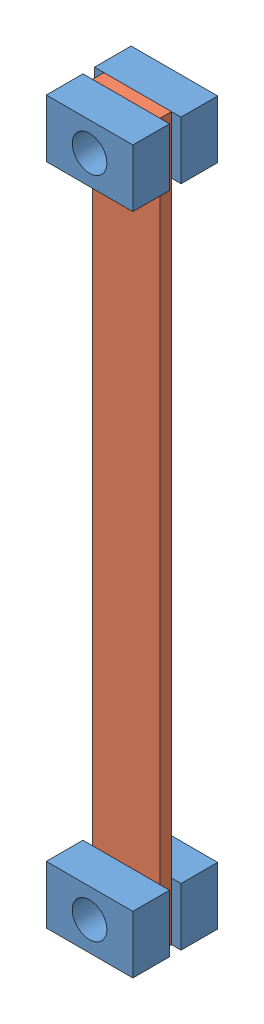
SolidWorks assembly Flywheel_CN_V2, configuration Default. Lengths in mm.
Overall size (15 125 14.7).
5 component instances, 2 part files, 11 mates.
Components (placement in the parent):
- PlaqueEpaisseFlywheel_CN_V2-1: PlaqueEpaisseFlywheel_CN_V2 [Default] at (0 57.5 1) size (15 10 6.35)
- PlaqueMinceFlywheel_CN_V2-1: PlaqueMinceFlywheel_CN_V2 [Default] x (-1 0 0) z (0 0 -1) size (11.7 125 2)
- PlaqueEpaisseFlywheel_CN_V2-2: PlaqueEpaisseFlywheel_CN_V2 [Default] at (0 -57.5 -1) x (-1 0 0) z (0 0 -1) size (15 10 6.35)
- PlaqueEpaisseFlywheel_CN_V2-3: PlaqueEpaisseFlywheel_CN_V2 [Default] at (0 -57.5 7.35) x (-1 0 0) z (0 0 -1) size (15 10 6.35)
- PlaqueEpaisseFlywheel_CN_V2-4: PlaqueEpaisseFlywheel_CN_V2 [Default] at (0 57.5 -1) x (-1 0 0) z (0 0 -1) size (15 10 6.35)
Mates (geometry in assembly coordinates):
- Coincident1: coincident aligned: circle of PlaqueEpaisseFlywheel_CN_V2-1; circle of PlaqueMinceFlywheel_CN_V2-1
- Parallel1: parallel anti-aligned: line of PlaqueEpaisseFlywheel_CN_V2-1 through (7.5 62.5 1) axis (-1 0 0); line of PlaqueMinceFlywheel_CN_V2-1 through (-5.85 62.5 -1) axis (1 0 0)
- Coincident3: coincident anti-aligned: circle of PlaqueMinceFlywheel_CN_V2-1; circle of PlaqueEpaisseFlywheel_CN_V2-4
- Coincident4: coincident aligned: line of PlaqueMinceFlywheel_CN_V2-1 through (-5.85 62.5 -1) axis (1 0 0); line of PlaqueEpaisseFlywheel_CN_V2-4 through (-7.5 62.5 -1) axis (1 0 0)
- Coincident5: coincident anti-aligned: circle of PlaqueMinceFlywheel_CN_V2-1; circle of PlaqueEpaisseFlywheel_CN_V2-2
- Coincident6: coincident anti-aligned: circle of PlaqueMinceFlywheel_CN_V2-1; circle of PlaqueEpaisseFlywheel_CN_V2-3
- Parallel2: parallel aligned: line of PlaqueMinceFlywheel_CN_V2-1 through (5.85 -62.5 1) axis (-1 0 0); line of PlaqueEpaisseFlywheel_CN_V2-2 through (7.5 -62.5 -1) axis (-1 0 0)
- Parallel3: parallel aligned: line of PlaqueMinceFlywheel_CN_V2-1 through (5.85 -62.5 1) axis (-1 0 0); line of PlaqueEpaisseFlywheel_CN_V2-3 through (7.5 -62.5 7.35) axis (-1 0 0)
- Coincident13: coincident anti-aligned: plane of PlaqueMinceFlywheel_CN_V2-1 through (0 0 0) normal (0 0 -1)
- Coincident14: coincident aligned: plane of PlaqueMinceFlywheel_CN_V2-1 through (0 0 0) normal (0 1 0)
- Coincident15: coincident anti-aligned: plane of PlaqueMinceFlywheel_CN_V2-1 through (0 0 0) normal (-1 0 0)
